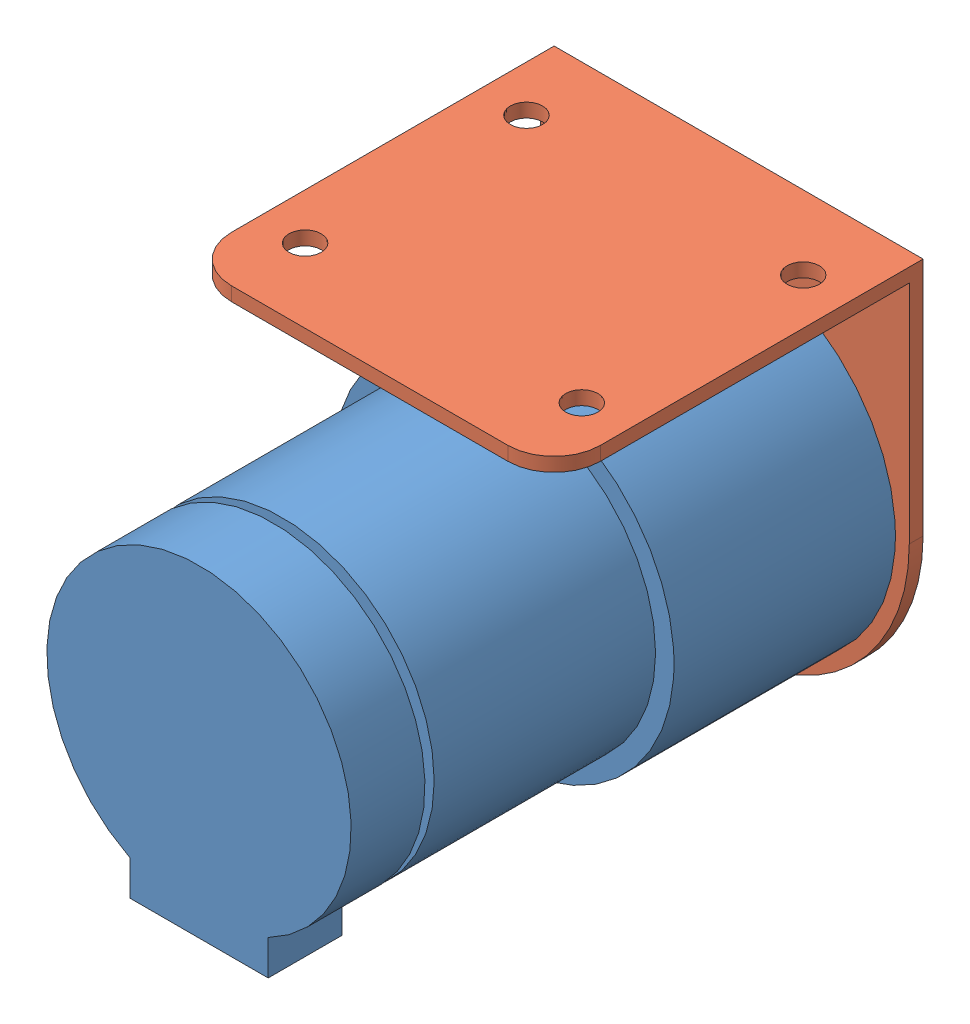
SolidWorks assembly 电机总装, configuration 默认. Lengths in mm.
Overall size (40 46 75).
8 component instances, 3 part files, 11 mates.
Components (placement in the parent):
- 减速比1：10【码盘减速电机】-1: 减速比1：10【码盘减速电机】 [默认] at (-64.1287 -78.3632 203.7151) x (1 0 0) z (0 0 -1) size (37 37 75)
- 电机支架-2: 电机支架 [默认] at (-64.1287 -78.3632 179.7151) x (1 0 0) z (0 0 -1) size (40 46 40)
- M3-8【内六角螺丝】-13: M3-8【内六角螺丝】 [默认] at (-56.3787 -64.9398 186.2151) x (-1 0 0) z (0 0 -1) size (4 4 10.5)
- M3-8【内六角螺丝】-14: M3-8【内六角螺丝】 [默认] at (-71.8787 -64.9398 186.2151) x (-0.5 -0.866025 0) z (0 0 -1) size (4 4 10.5)
- M3-8【内六角螺丝】-15: M3-8【内六角螺丝】 [默认] at (-79.6287 -78.3632 186.2151) x (0.5 -0.866025 0) z (0 0 -1) size (4 4 10.5)
- M3-8【内六角螺丝】-16: M3-8【内六角螺丝】 [默认] at (-71.8787 -91.7866 186.2151) x (1 0 0) z (0 0 -1) size (4 4 10.5)
- M3-8【内六角螺丝】-17: M3-8【内六角螺丝】 [默认] at (-56.3787 -91.7866 186.2151) x (0.5 0.866025 0) z (0 0 -1) size (4 4 10.5)
- M3-8【内六角螺丝】-18: M3-8【内六角螺丝】 [默认] at (-48.6287 -78.3632 186.2151) x (-0.5 0.866025 0) z (0 0 -1) size (4 4 10.5)
Mates (geometry in assembly coordinates):
- 同心3: concentric: cylinder of ? through (-55.2341 -92.6526 159.7151) axis (0 0 -1) radius 1.5; cylinder of ? through (-55.2341 -92.6526 159.7151) axis (0 0 -1) radius 1.5
- 重合2: coincident: plane of ? through (-64.1287 -85.3632 159.7151) normal (0 0 1); plane of ? through (-55.2341 -92.6526 159.7151) normal (0 0 -1)
- 同心5: concentric: cylinder of ? through (-64.1287 -85.3632 155.7151) axis (0 0 1) radius 3; cylinder of 减速比1：10【码盘减速电机】-1 through (-64.1287 -85.3632 161.7151) axis (0 0 1) radius 3
- 距离1: distance = 2 mm: plane of ? through (-64.1287 -85.3632 171.7151) normal (0 0 1); plane of 减速比1：10【码盘减速电机】-1 through (-64.1287 -85.3632 173.7151) normal (0 0 -1)
- 同心6: concentric: cylinder of 减速比1：10【码盘减速电机】-1 through (-64.1287 -85.3632 173.7151) axis (0 0 1) radius 5; cylinder of ? through (-64.1287 -85.3632 178.2151) axis (0 0 1) radius 5
- 重合5: coincident: plane of 减速比1：10【码盘减速电机】-1 through (-64.1287 -78.3632 179.7151) normal (0 0 -1); plane of ? through (-65.7369 -78.0377 179.7151) normal (0 0 1)
- 重合7: coincident: plane of assembly; plane of assembly; plane of 减速比1：10【码盘减速电机】-1 through (-64.1287 -78.3632 179.7151) normal (0 0 -1); plane of 电机支架-2 through (-64.1287 -78.3632 179.7151) normal (0 0 1)
- 同心14: concentric: cylinder of assembly; cylinder of assembly; cylinder of 减速比1：10【码盘减速电机】-1 through (-71.8787 -64.9398 184.7151) axis (0 0 -1) radius 1.5; cylinder of 电机支架-2 through (-71.8787 -64.9398 178.2151) axis (0 0 1) radius 1.5
- 同心15: concentric: cylinder of assembly; cylinder of assembly; cylinder of 减速比1：10【码盘减速电机】-1 through (-56.3787 -64.9398 184.7151) axis (0 0 -1) radius 1.5; cylinder of 电机支架-2 through (-56.3787 -64.9398 178.2151) axis (0 0 1) radius 1.5
- 同心16: concentric: cylinder of assembly; cylinder of assembly; cylinder of 电机支架-2 through (-56.3787 -64.9398 178.2151) axis (0 0 1) radius 1.5; cylinder of M3-8【内六角螺丝】-13 through (-56.3787 -64.9398 178.2151) axis (0 0 1) radius 1.5
- 重合8: coincident: plane of assembly; plane of assembly; plane of 电机支架-2 through (-64.1287 -78.3632 178.2151) normal (0 0 -1); plane of M3-8【内六角螺丝】-13 through (-56.3787 -64.9398 178.2151) normal (0 0 1)
